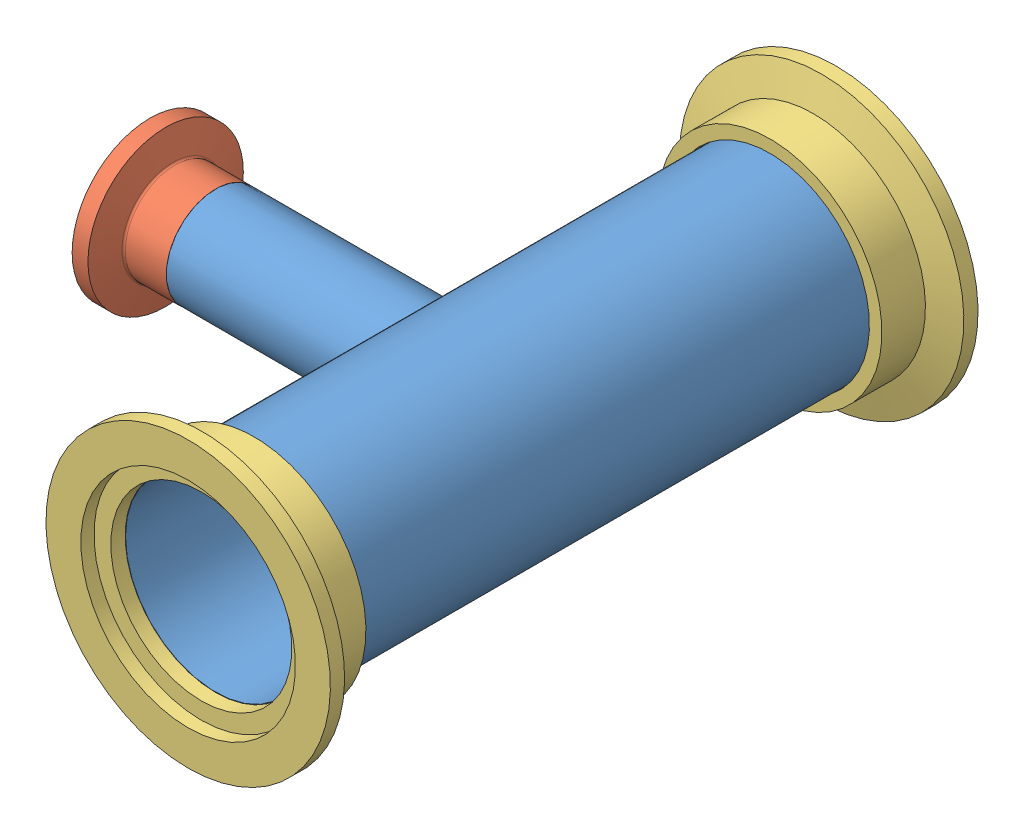
SolidWorks assembly 724011, configuration Default. Lengths in mm.
Overall size (103 66.3 124.92).
4 component instances, 3 part files, 6 mates.
Components (placement in the parent):
- 404545-1: 404545 [Default] at (72.1095 62.4896 80.3195) size (76.2 38.1 114.3)
- 713001-1: 713001 [Default] at (2.2595 62.4896 80.3195) x (0 0 -1) z (1 0 0) size (29.97 29.97 14.22)
- 713003-99-1: 713003-99 [Default] at (72.1095 62.4896 17.8609) x (0.971545 0.236856 0) z (-0.236856 0.971545 0) size (54.86 12.7 54.86)
- 713003-99-2: 713003-99 [Default] at (72.1095 62.4896 142.7781) x (1 0 0) z (0 -1 0) size (54.86 12.7 54.86)
Mates (geometry in assembly coordinates):
- Coincident1: coincident anti-aligned: plane of 404545-1 through (14.9595 62.4896 80.3195) normal (-1 0 0); plane of 713001-1 through (14.9595 62.4896 71.8105) normal (1 0 0)
- Concentric1: concentric anti-aligned: cylinder of 404545-1 through (14.9595 62.4896 80.3195) axis (1 0 0) radius 9.525; cylinder of 713001-1 through (2.2595 62.4896 80.3195) axis (-1 0 0) radius 9.525
- Coincident2: coincident anti-aligned: plane of 404545-1 through (72.1095 62.4896 137.4695) normal (0 0 1); plane of 713003-99-2 through (91.2865 62.4896 137.4695) normal (0 0 -1)
- Concentric2: concentric anti-aligned: cylinder of 404545-1 through (72.1095 62.4896 137.4695) axis (0 0 -1) radius 19.05; cylinder of 713003-99-2 through (72.1095 62.4896 142.7781) axis (0 0 1) radius 21.59
- Coincident3: coincident anti-aligned: plane of 404545-1 through (72.1095 62.4896 23.1695) normal (0 0 -1); plane of 713003-99-1 through (90.7408 67.0318 23.1695) normal (0 0 1)
- Concentric3: concentric aligned: cylinder of 404545-1 through (72.1095 62.4896 137.4695) axis (0 0 -1) radius 19.05; cylinder of 713003-99-1 through (72.1095 62.4896 17.8609) axis (0 0 -1) radius 21.59
